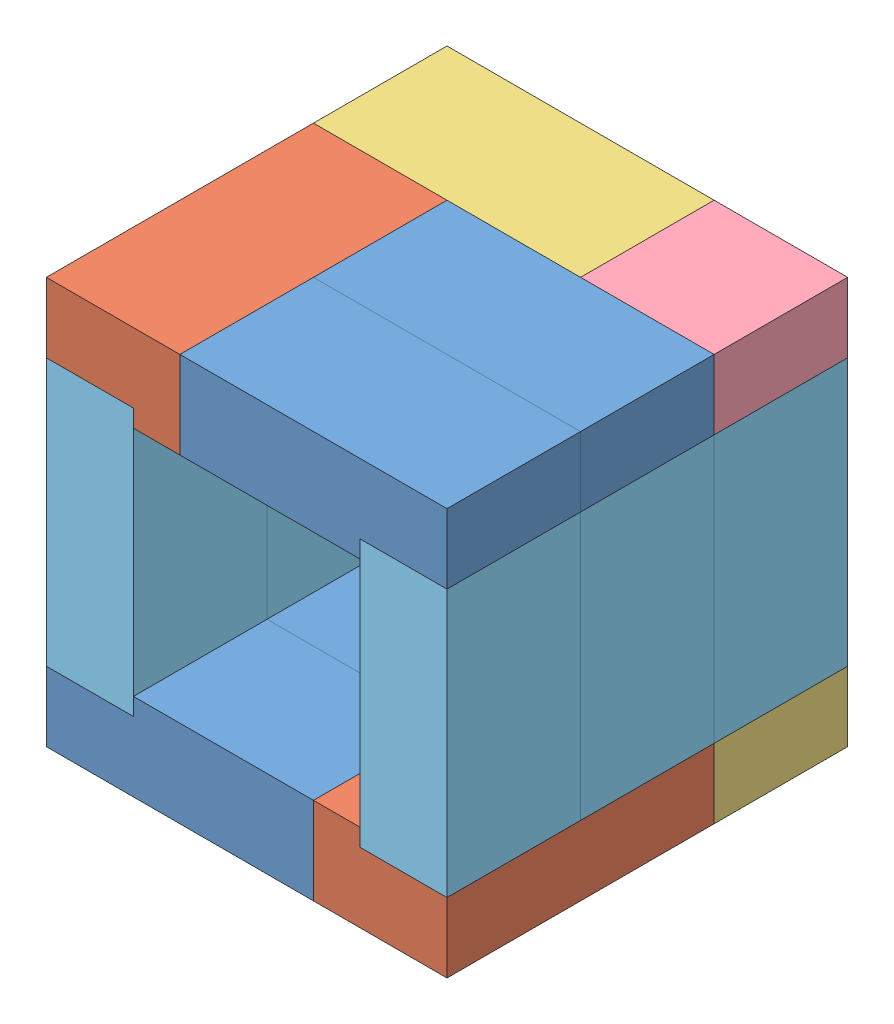
SolidWorks assembly Assem6, configuration Default. Lengths in mm.
Overall size (351.06 350 350.32).
23 component instances, 6 part files, 11 mates.
Components (placement in the parent):
- Heat Treat Asm Top-Bot Alt 2-1: Heat Treat Asm Top-Bot Alt 2 [Default] at origin size (345 75 345)
  - Brick-Sharp-BackCut-1: Brick-Sharp-BackCut [Default] at (102.0414 124.8114 164.7515) size (230 75 115)
  - Brick-Sharp-SideCut-1: Brick-Sharp-SideCut [Default] at (274.5414 124.8114 107.2515) x (0 0 1) z (-1 0 0) size (230 75 115)
  - Brick-Sharp-BackCut-2: Brick-Sharp-BackCut [Default] at (102.0414 124.8114 49.7515) size (230 75 115)
  - Brick-Sharp-BackLeftCut-1: Brick-Sharp-BackLeftCut [Default] at (217.0414 124.8114 -65.2485) x (-1 0 0) z (0 0 -1) size (230 75 115)
  - Brick-Sharp-BackRightCutTrimmed-1: Brick-Sharp-BackRightCutTrimmed [Default] at (102.0414 124.8114 -65.2485) size (115 75 115)
- Heat Treat Asm Side-1: Heat Treat Asm Side [Default] at (466.0458 137.1783 -153.9966) x (-0.008726 0.008727 0.999924) z (-0.999962 0 -0.008727) size (347.64 233.01 78.01)
  - Brick-Sharp-1: Brick-Sharp [Default] at (91.3299 124.3408 170.7235) x (-0.008727 -0.999962 0) z (-0.999924 0.008726 0.008727) size (230 75 115)
  - Brick-Sharp-2: Brick-Sharp [Default] at (206.3211 123.3373 169.7199) x (0.008727 0.999962 0) z (-0.999924 0.008726 0.008727) size (230 75 115)
  - Brick-Sharp-4: Brick-Sharp [Default] at (321.3124 122.3338 168.7164) x (-0.008727 -0.999962 0) z (0.999924 -0.008726 -0.008727) size (230 75 115)
- Heat Treat Asm Side-2: Heat Treat Asm Side [Default] at (-146.9631 137.1783 253.4996) x (0.008726 0.008727 -0.999924) z (0.999962 0 0.008727) size (347.64 233.01 78.01)
  - Brick-Sharp-1: Brick-Sharp [Default] at (91.3299 124.3408 170.7235) x (-0.008727 -0.999962 0) z (-0.999924 0.008726 0.008727) size (230 75 115)
  - Brick-Sharp-2: Brick-Sharp [Default] at (206.3211 123.3373 169.7199) x (0.008727 0.999962 0) z (-0.999924 0.008726 0.008727) size (230 75 115)
  - Brick-Sharp-4: Brick-Sharp [Default] at (321.3124 122.3338 168.7164) x (-0.008727 -0.999962 0) z (0.999924 -0.008726 -0.008727) size (230 75 115)
- Heat Treat Asm Back Alt-1: Heat Treat Asm Back Alt [Default] at (25.7736 342.4195 43.3274) x (0 -1 0) z (1 0 0) size (230 75 195)
  - Brick-Sharp-1: Brick-Sharp [Default] at (80.1081 128.5759 173.7678) size (230 75 115)
  - Brick-Sharp-Trimmed-1: Brick-Sharp-Trimmed [Default] at (80.1081 128.5759 58.7678) size (230 75 80)
- Heat Treat Asm Top-Bot Alt 2-2: Heat Treat Asm Top-Bot Alt 2 [Default] at (319.0827 524.6228 0) x (-1 0 0) z (0 0 1) size (345 75 345)
  - Brick-Sharp-BackCut-1: Brick-Sharp-BackCut [Default] at (102.0414 124.8114 164.7515) size (230 75 115)
  - Brick-Sharp-SideCut-1: Brick-Sharp-SideCut [Default] at (274.5414 124.8114 107.2515) x (0 0 1) z (-1 0 0) size (230 75 115)
  - Brick-Sharp-BackCut-2: Brick-Sharp-BackCut [Default] at (102.0414 124.8114 49.7515) size (230 75 115)
  - Brick-Sharp-BackLeftCut-1: Brick-Sharp-BackLeftCut [Default] at (217.0414 124.8114 -65.2485) x (-1 0 0) z (0 0 -1) size (230 75 115)
  - Brick-Sharp-BackRightCutTrimmed-1: Brick-Sharp-BackRightCutTrimmed [Default] at (102.0414 124.8114 -65.2485) size (115 75 115)
Mates (geometry in assembly coordinates):
- Coincident1: coincident: line of Heat Treat Asm Top-Bot Alt 2-1/Brick-Sharp-SideCut-1 through (257.0414 147.3114 222.2515) axis (1 0 0); line of Heat Treat Asm Side-1/Brick-Sharp-4 through (332.0414 147.3114 222.2515) axis (-1 0 0)
- Coincident2: coincident: plane of Heat Treat Asm Top-Bot Alt 2-1/Brick-Sharp-SideCut-1 through (274.5414 147.3114 107.2515) normal (0 1 0); plane of Heat Treat Asm Side-1/Brick-Sharp-4 through (332.0414 147.3114 107.2515) normal (0 -1 0)
- Coincident3: coincident anti-aligned: line of Heat Treat Asm Top-Bot Alt 2-1/Brick-Sharp-SideCut-1 through (257.0414 147.3114 -7.7485) axis (0 0 1); line of Heat Treat Asm Side-1/Brick-Sharp-4 through (257.0414 147.3114 222.2515) axis (0 0 -1)
- Coincident4: coincident: plane of Heat Treat Asm Top-Bot Alt 2-1/Brick-Sharp-BackLeftCut-1 through (217.0414 147.3114 -65.2485) normal (0 1 0); plane of Heat Treat Asm Back Alt-1/Brick-Sharp-1 through (142.0414 147.3114 -122.7485) normal (0 -1 0)
- Coincident5: coincident: plane of Heat Treat Asm Side-1/Brick-Sharp-1 through (257.0414 262.3114 -65.2485) normal (-1 0 0); plane of Heat Treat Asm Back Alt-1/Brick-Sharp-1 through (257.0414 377.3114 -122.7485) normal (1 0 0)
- Coincident6: coincident aligned: line of Heat Treat Asm Top-Bot Alt 2-1/Brick-Sharp-BackLeftCut-1 through (332.0414 147.3114 -122.7485) axis (-1 0 0); line of Heat Treat Asm Back Alt-1/Brick-Sharp-1 through (257.0414 147.3114 -122.7485) axis (-1 0 0)
- Coincident7: coincident: line of Heat Treat Asm Top-Bot Alt 2-1/Brick-Sharp-BackRightCutTrimmed-1 through (102.0414 147.3114 -122.7485) axis (-1 0 0); line of Heat Treat Asm Side-2/Brick-Sharp-4 through (-12.9586 147.3114 -122.7485) axis (1 0 0)
- Coincident8: coincident anti-aligned: line of Heat Treat Asm Top-Bot Alt 2-1/Brick-Sharp-BackCut-1 through (-12.9586 147.3114 107.2515) axis (0 0 1); line of Heat Treat Asm Side-2/Brick-Sharp-1 through (-12.9586 147.3114 222.2515) axis (0 0 -1)
- Coincident9: coincident: plane of Heat Treat Asm Back Alt-1/Brick-Sharp-1 through (142.0414 377.3114 -122.7485) normal (0 1 0); plane of Heat Treat Asm Top-Bot Alt 2-2/Brick-Sharp-BackLeftCut-1 through (102.0414 377.3114 -65.2485) normal (0 -1 0)
- Coincident10: coincident: line of Heat Treat Asm Back Alt-1/Brick-Sharp-Trimmed-1 through (62.0414 377.3114 -122.7485) axis (1 0 0); line of Heat Treat Asm Top-Bot Alt 2-2/Brick-Sharp-BackLeftCut-1 through (-12.9586 377.3114 -122.7485) axis (1 0 0)
- Coincident11: coincident anti-aligned: line of Heat Treat Asm Side-2/Brick-Sharp-1 through (-12.9586 377.3114 107.2515) axis (0 0 1); line of Heat Treat Asm Top-Bot Alt 2-2/Brick-Sharp-SideCut-1 through (-12.9586 377.3114 222.2515) axis (0 0 -1)
